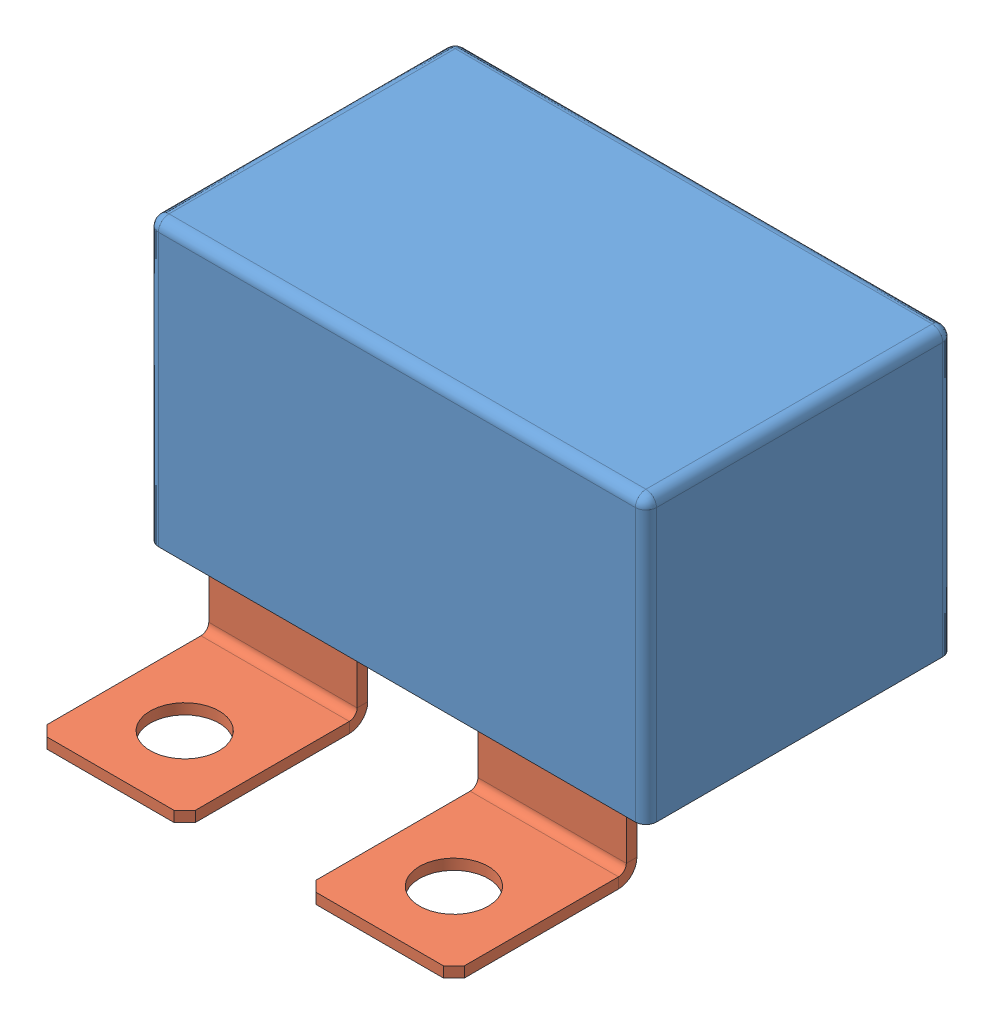
SolidWorks assembly silta_konkka_assy, configuration Default. Lengths in mm.
Overall size (47 33.23 44.27).
3 component instances, 2 part files, 5 mates.
Components (placement in the parent):
- silta_konkka_runko-1: silta_konkka_runko [Default] at (-13.8171 10.837 -0.0714) size (47 26.7 29)
- silta_konkka_jalka-1: silta_konkka_jalka [Default] at (4.9329 4.3062 15.1986) x (0 0 -1) z (1 0 0) size (17.27 6.53 14)
- silta_konkka_jalka-2: silta_konkka_jalka [Default] at (30.3329 4.3062 15.1986) x (0 0 -1) z (1 0 0) size (17.27 6.53 14)
Mates (geometry in assembly coordinates):
- Distance1: distance = 25.4 mm: point of silta_konkka_jalka-1; point of silta_konkka_jalka-2
- Distance2: distance = 11.4 mm anti-aligned: plane of silta_konkka_jalka-1 through (4.9329 5.3062 14.1986) normal (1 0 0); plane of silta_konkka_jalka-2 through (16.3329 5.3062 14.1986) normal (-1 0 0)
- Coincident4: coincident anti-aligned: plane of silta_konkka_jalka-1 through (4.9329 10.837 -1.0714) normal (0 1 0); plane of silta_konkka_runko-1 through (-13.8171 10.837 -29.0714) normal (0 -1 0)
- Distance3: distance = 2.85 mm aligned: plane of silta_konkka_jalka-2 through (30.3329 -10.433 -1.0714) normal (1 0 0); plane of silta_konkka_runko-1 through (33.1829 37.537 -0.0714) normal (1 0 0)
- Distance4: distance = 1 mm aligned: plane of silta_konkka_jalka-2 through (16.3329 10.837 -1.0714) normal (0 0 1); plane of silta_konkka_runko-1 through (-13.8171 37.537 -0.0714) normal (0 0 1)
